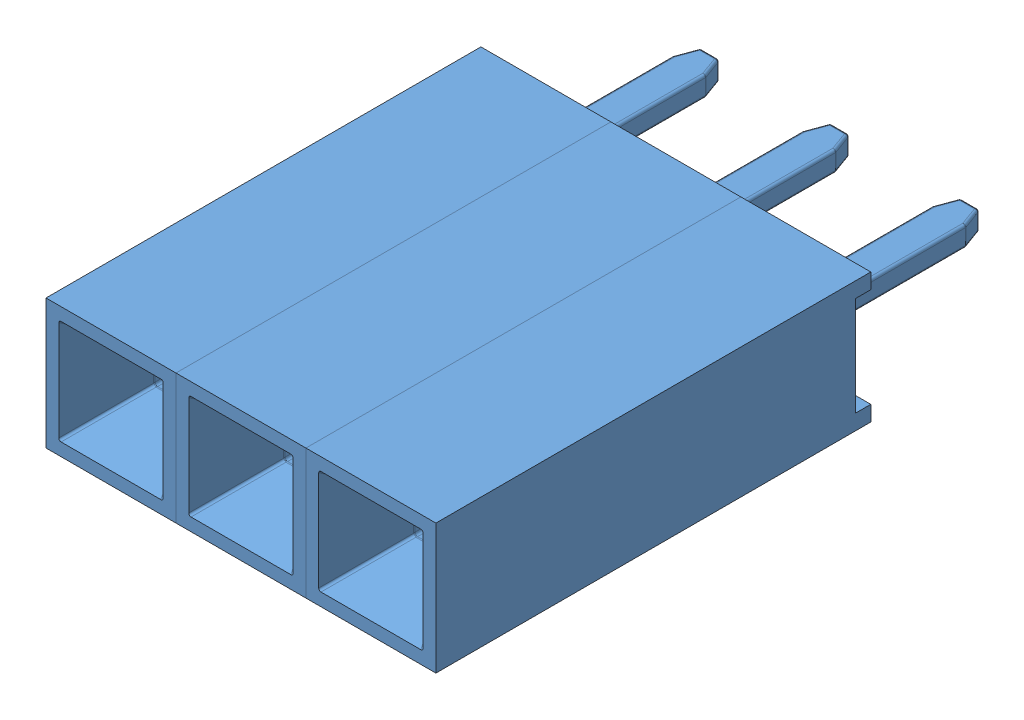
SolidWorks assembly Female Pin Header 01x03 Pitch 2.54mm Height 8.5mm.stp, configuration Valor predeterminado. Lengths in mm.
Overall size (7.62 2.54 11.7).
3 component instances, 1 part files, 0 mates.
Components (placement in the parent):
- Female Pin Header 1x.stp-1: Female Pin Header 1x.stp [Valor predeterminado] at origin size (2.54 2.54 11.7)
- Female Pin Header 1x.stp-2: Female Pin Header 1x.stp [Valor predeterminado] at (2.54 0 0) size (2.54 2.54 11.7)
- Female Pin Header 1x.stp-3: Female Pin Header 1x.stp [Valor predeterminado] at (5.08 0 0) size (2.54 2.54 11.7)
